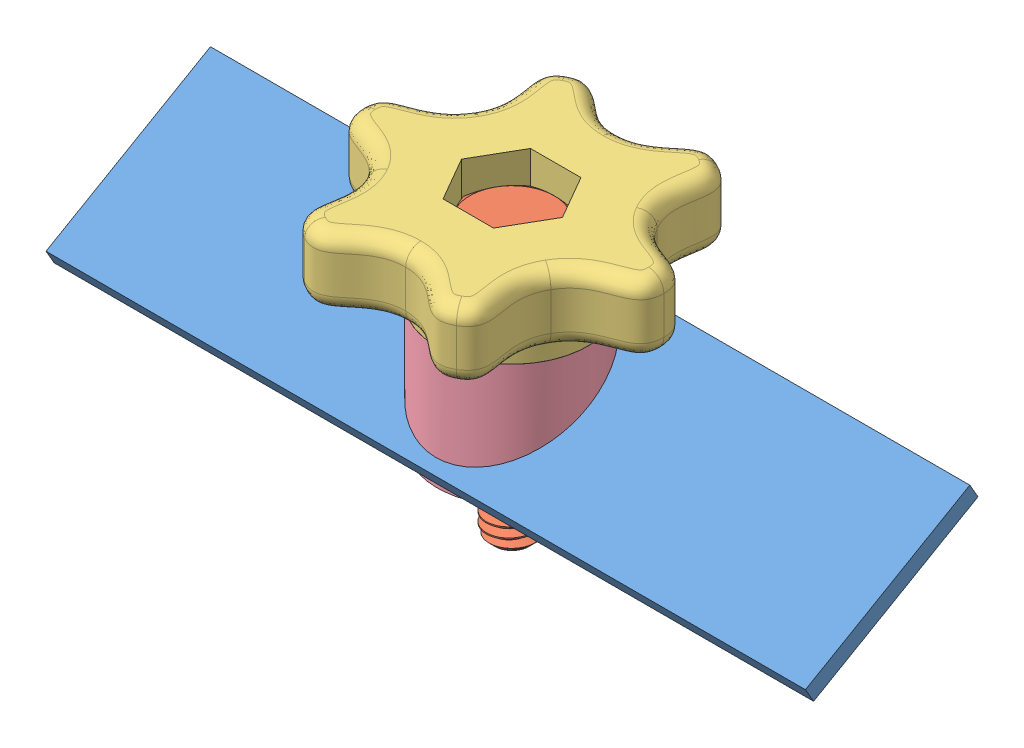
SolidWorks assembly WorkLightMount, configuration Default. Lengths in mm.
Overall size (100 40.22 37.39).
5 component instances, 4 part files, 12 mates.
Components (placement in the parent):
- LightBracket-1: LightBracket [Default] at (0 -13.181 0) x (1 0 0) z (0 -0.5 0.866025) size (100 2.15 25)
- 1-4-20x1.25-1: 1-4-20x1.25 [91236A544] at (0 -13.6922 0) x (0 -1 0) z (0.866025 0 -0.5) size (36.58 12.83 11.11)
- BoltKnob-1: BoltKnob [Default] at (0 4.3656 0) size (41.74 13 37.39)
- AngledSpacer-1: AngledSpacer [Default] at origin size (20 12.71 20)
- AngledSpacer-2: AngledSpacer [Default] at (0.159 -26.2659 -0.1664) x (0.999717 0.011893 -0.020599) z (-0.020599 -0.000123 -0.999788) size (20 12.71 20)
Mates (geometry in assembly coordinates):
- Coincident1: coincident: line of 1-4-20x1.25-1 through (0 8.5282 0) axis (0 -1 0); plane of assembly
- Coincident2: coincident: line of 1-4-20x1.25-1 through (0 8.5282 0) axis (0 -1 0); plane of assembly
- Coincident3: coincident anti-aligned: plane of 1-4-20x1.25-1 through (3.2079 0 -5.5563) normal (0 -1 0); plane of assembly through (0 0 0) normal (0 1 0)
- Parallel1: parallel: line of LightBracket-1 through (-50 -18.5 11.3628) axis (1 0 0); plane of assembly
- Coincident4: coincident: point of LightBracket-1; line of 1-4-20x1.25-1 through (0 8.5282 0) axis (0 -1 0)
- Angle1: planar angle = 0.523599 rad aligned: plane of LightBracket-1 through (0 -12.25 0.5375) normal (0 0.866025 0.5); plane of 1-4-20x1.25-1 through (3.2079 4.3656 -5.5563) normal (0 1 0)
- Coincident5: coincident: point of 1-4-20x1.25-1; plane of assembly
- Concentric1: concentric anti-aligned: cylinder of 1-4-20x1.25-1 through (0 0 0) axis (0 -1 0) radius 3.175; cylinder of BoltKnob-1 through (0 -5 0) axis (0 1 0) radius 3.375
- Coincident6: coincident anti-aligned: plane of 1-4-20x1.25-1 through (3.2079 0 -5.5563) normal (0 -1 0); plane of BoltKnob-1 through (0 0 0) normal (0 1 0)
- Parallel2: parallel anti-aligned: plane of 1-4-20x1.25-1 through (6.4158 4.3656 0) normal (0.866025 0 -0.5); plane of BoltKnob-1 through (6.6467 -1 0) normal (-0.866025 0 0.5)
- Distance1: distance = 1 mm: line of LightBracket-1 through (50 -6 -10.2878) axis (-1 0 0); plane of BoltKnob-1 through (0 -5 0) normal (0 -1 0)
- Coincident9: coincident anti-aligned: plane of LightBracket-1 through (0 -14.112 -0.5375) normal (0 -0.866025 -0.5); plane of AngledSpacer-2 through (0.0022 -14.0168 -0.7023) normal (0 0.866025 0.5)
